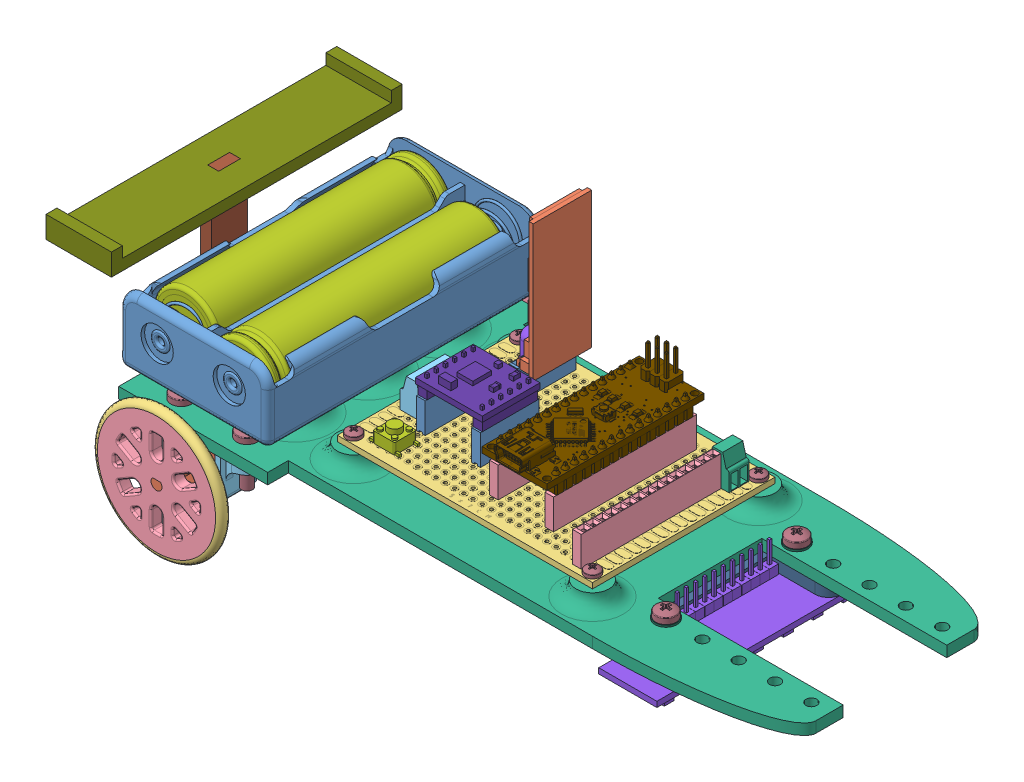
SolidWorks assembly LFR1_Assembly LFR, configuration Default. Lengths in mm.
Overall size (193.57 76.3 96.2).
59 component instances, 26 part files, 125 mates.
Components (placement in the parent):
- Battery holder 2 x 18650-1: Battery holder 2 x 18650 [Default] at (0 30.75 0) x (0 0 -1) z (0 1 0) size (76 41.1 19)
- Micro Metal Gear Motor-1: Micro Metal Gear Motor [Default] at (0 17.75 29) size (12 10 35.9)
- Micro Metal Gear Motor-2: Micro Metal Gear Motor [Default] at (0 17.75 -29) x (-1 0 0) z (0 0 -1) size (12 10 35.9)
- O-ring 29.5 x 3-1: O-ring 29.5 x 3 [Default] at (0 17.75 46.6) size (35.5 35.5 3)
- O-ring 29.5 x 3-2: O-ring 29.5 x 3 [Default] at (0 17.75 -46.6) size (35.5 35.5 3)
- Wiel 29.5 x 3-1: Wiel 29.5 x 3 [Default] at (0 17.75 46.6) size (32.5 32.5 3)
- Wiel 29.5 x 3-2: Wiel 29.5 x 3 [Default] at (0 17.75 -46.6) x (-1 0 0) z (0 0 -1) size (32.5 32.5 3)
- Micro Metal Gear Motor Bracket-1: Micro Metal Gear Motor Bracket [Default] at (0 22.75 33) x (-1 0 0) z (0 0 1) size (26.6 11.5 10)
- Micro Metal Gear Motor Bracket-2: Micro Metal Gear Motor Bracket [Default] at (0 22.75 -33) x (1 0 0) z (0 0 -1) size (26.6 11.5 10)
- Base-1: Base [Default] at (0 22.75 0) size (175.57 8.18 76)
- Battery 2 x 18650-1: Battery 2 x 18650 [Default] at (0 30.75 0) x (0 0 1) z (0 1 0) size (69.6 38.05 18.2)
- QTR-8A-2: QTR-8A [Default] at (114.575 18.25 0) x (0 0 -1) z (-1 0 0) size (66 11.64 16)
- M3 Ronde Kop-1: M3 Ronde Kop [Default] at (102.525 8 0) x (0 0 -1) z (1 0 0) size (5.77 15 5)
- QTR-8A plaatje-1: QTR-8A plaatje [Default] at (110.075 19.75 0) x (-1 0 0) z (0 0 -1) size (23.8 14.75 43.5)
- Spoiler deel 1-1: Spoiler deel 1 [Default] at (28 19.75 0) size (45.92 36 10)
- hex thin nut chamfered gradeab_iso-1: hex thin nut chamfered gradeab_iso [ISO - 4035 - M3 - C] at (-9.05 19.45 32.25) x (1 0 0) z (0 -1 0) size (5.5 6.35 1.8)
- hex thin nut chamfered gradeab_iso-2: hex thin nut chamfered gradeab_iso [ISO - 4035 - M3 - C] at (-9.05 19.45 -32.25) x (1 0 0) z (0 -1 0) size (5.5 6.35 1.8)
- hex thin nut chamfered gradeab_iso-3: hex thin nut chamfered gradeab_iso [ISO - 4035 - M3 - C] at (9.05 21.25 -32.25) x (-0.5 0 0.866025) z (0 1 0) size (5.5 6.35 1.8)
- hex thin nut chamfered gradeab_iso-4: hex thin nut chamfered gradeab_iso [ISO - 4035 - M3 - C] at (9.05 19.45 32.25) x (1 0 0) z (0 -1 0) size (5.5 6.35 1.8)
- pan head cross recess screw_iso-13: pan head cross recess screw_iso [ISO 7045 - M3 x 12 - Z - 12N] at (-9.05 28.15 -32.25) x (0 -1 0) z (0 0 1) size (14.35 5.6 5.6)
- pan head cross recess screw_iso-14: pan head cross recess screw_iso [ISO 7045 - M3 x 12 - Z - 12N] at (9.05 28.15 32.25) x (0 -1 0) z (0 0 1) size (14.35 5.6 5.6)
- pan head cross recess screw_iso-15: pan head cross recess screw_iso [ISO 7045 - M3 x 12 - Z - 12N] at (9.05 28.15 -32.25) x (0 -1 0) z (0 0 1) size (14.35 5.6 5.6)
- pan head cross recess screw_iso-16: pan head cross recess screw_iso [ISO 7045 - M3 x 12 - Z - 12N] at (-9.05 28.15 32.25) x (0 -1 0) z (0 0 1) size (14.35 5.6 5.6)
- hex thin nut chamfered gradeab_iso-5: hex thin nut chamfered gradeab_iso [ISO - 4035 - M3 - C] at (-9.925 19.75 0) x (1 0 0) z (0 1 0) size (5.5 6.35 1.8)
- hex thin nut chamfered gradeab_iso-6: hex thin nut chamfered gradeab_iso [ISO - 4035 - M3 - C] at (9.925 19.75 0) x (1 0 0) z (0 1 0) size (5.5 6.35 1.8)
- countersunk flat head cross recess screw_iso-4: countersunk flat head cross recess screw_iso [ISO 7046-1 - M3 x 16 - Z - 16N] at (9.925 32.65 0) x (0 -1 0) z (0 0 1) size (16 5.5 5.5)
- countersunk flat head cross recess screw_iso-5: countersunk flat head cross recess screw_iso [ISO 7046-1 - M3 x 16 - Z - 16N] at (-9.925 32.65 0) x (0 -1 0) z (0 0 1) size (16 5.5 5.5)
- pan head cross recess screw_iso-19: pan head cross recess screw_iso [ISO 7045 - M2 x 6 - Z - 6N] at (29 32.89 22.85) x (0 -1 0) z (0 0 1) size (7.57 4 4)
- pan head cross recess screw_iso-20: pan head cross recess screw_iso [ISO 7045 - M2 x 6 - Z - 6N] at (94.7 32.89 -22.85) x (0 -1 0) z (1 0 0) size (7.57 4 4)
- pan head cross recess screw_iso-21: pan head cross recess screw_iso [ISO 7045 - M2 x 6 - Z - 6N] at (29 32.89 -22.85) x (0 -1 0) z (0 0 1) size (7.57 4 4)
- pan head cross recess screw_iso-22: pan head cross recess screw_iso [ISO 7045 - M2 x 6 - Z - 6N] at (94.7 32.89 22.85) x (0 -1 0) z (0 0 1) size (7.57 4 4)
- plain washer small grade a_iso-1: plain washer small grade a_iso [Washer ISO 7092 - 2] at (94.7 29.75 22.85) x (0 -1 0) z (0 0 1) size (0.3 4.5 4.5)
- plain washer small grade a_iso-2: plain washer small grade a_iso [Washer ISO 7092 - 2] at (29 29.75 22.85) x (0 -1 0) z (0 0 1) size (0.3 4.5 4.5)
- plain washer small grade a_iso-3: plain washer small grade a_iso [Washer ISO 7092 - 2] at (94.7 29.75 -22.85) x (0 -1 0) z (0 0 1) size (0.3 4.5 4.5)
- plain washer small grade a_iso-4: plain washer small grade a_iso [Washer ISO 7092 - 2] at (29 29.75 -22.85) x (0 -1 0) z (0 0 1) size (0.3 4.5 4.5)
- plain washer small grade a_iso-5: plain washer small grade a_iso [Washer ISO 7092 - 3] at (110.075 18.25 -18) x (0 1 0) z (-1 0 0) size (0.5 6 6)
- plain washer small grade a_iso-6: plain washer small grade a_iso [Washer ISO 7092 - 3] at (110.075 18.25 18) x (0 1 0) z (-1 0 0) size (0.5 6 6)
- plain washer small grade a_iso-7: plain washer small grade a_iso [Washer ISO 7092 - 3] at (110.075 25.75 18) x (0 -1 0) z (-1 0 0) size (0.5 6 6)
- plain washer small grade a_iso-8: plain washer small grade a_iso [Washer ISO 7092 - 3] at (110.075 25.75 -18) x (0 -1 0) z (-1 0 0) size (0.5 6 6)
- pan head cross recess screw_iso-23: pan head cross recess screw_iso [ISO 7045 - M3 x 10 - Z - 10N] at (110.075 28.65 18) x (0 -1 0) z (-1 0 0) size (12.35 5.6 5.6)
- pan head cross recess screw_iso-24: pan head cross recess screw_iso [ISO 7045 - M3 x 10 - Z - 10N] at (110.075 28.65 -18) x (0 -1 0) z (-1 0 0) size (12.35 5.6 5.6)
- hex thin nut chamfered gradeab_iso-7: hex thin nut chamfered gradeab_iso [ISO - 4035 - M3 - C] at (110.075 15.95 18) x (-1 0 0) z (0 -1 0) size (5.5 6.35 1.8)
- hex thin nut chamfered gradeab_iso-8: hex thin nut chamfered gradeab_iso [ISO - 4035 - M3 - C] at (110.075 15.95 -18) x (-1 0 0) z (0 -1 0) size (5.5 6.35 1.8)
- Spoiler deel 2-1: Spoiler deel 2 [Default] at (-29.5 52.75 0) size (18 6 80)
- PCB assembly-1: PCB assembly [Default] at (61.85 29.75 0) size (70.2 48.6 50.2)
  - DRV8833-1: DRV8833 [Default] at (-16.49 13.955 5.08) size (18.4 11.9 15.9)
  - Arduino Nano-1: Arduino Nano [Default] at (16.8088 23.6188 0.3902) x (0 0 1) z (-1 0 0) size (44.95 20.74 17.81)
  - Header6P-1: Header6P [Default] at (-24.09 1.555 -1.27) x (0 0 1) z (0 1 0) size (16.1 2.4 11.5)
  - Header6P-2: Header6P [Default] at (-8.89 1.555 -1.27) x (0 0 1) z (0 1 0) size (16.1 2.4 11.5)
  - HC-05-2: HC-05 [Varsayılan] at (-13.49 46.555 -23.29) x (0 -1 0) z (-1 0 0) size (42.6 16.1 5.9)
  - Header6P-3: Header6P [Default] at (-19.04 1.555 -21.59) x (0 0 1) z (0 1 0) size (16.1 2.4 11.5)
  - PCB 50 x 70-1: PCB 50 x 70 [Default] x (1 0 0) z (0 1 0) size (70.2 50.2 1.66)
  - Header15P-1: Header15P [Default] at (1.2888 2.355 16.51) x (0 0 1) z (0 1 0) size (39.38 2.4 11.5)
  - Header15P-2: Header15P [Default] at (16.51 2.355 16.51) x (0 0 1) z (0 1 0) size (39.38 2.4 11.5)
  - Header15P-3: Header15P [Default] at (29.21 2.355 -13.97) x (0 0 -1) z (0 1 0) size (39.38 2.4 11.5)
  - ScrewTerminal x 4-1: ScrewTerminal x 4 [Default] at (-29.4 1.555 5.08) x (0 0 1) z (-1 0 0) size (10.62 12.4 6.3)
  - ScrewTerminal x 2-1: ScrewTerminal x 2 [Default] at (29.41 1.555 -17.78) x (0 0 -1) z (1 0 0) size (5.54 12.4 6.3)
  - Push button-1: Push button [Default] at (-25.39 1.555 19.05) size (8.26 7.7 6)
  - Led-1: Led [Default] at (-25.39 1.555 -19.05) size (5.8 11.9 5.8)
Mates (geometry in assembly coordinates):
- Concentric1: concentric anti-aligned: cylinder of Micro Metal Gear Motor-1 through (0 17.75 48.1) axis (0 0 -1) radius 1.5; cylinder of Micro Metal Gear Motor-2 through (0 17.75 -48.1) axis (0 0 1) radius 1.5
- Coincident32: coincident aligned: plane of Micro Metal Gear Motor-1 through (3.1623 22.75 15) normal (0 1 0); plane of Micro Metal Gear Motor-2 through (-3.1623 22.75 -15) normal (0 1 0)
- Concentric2: concentric anti-aligned: cylinder of Micro Metal Gear Motor-1 through (0 17.75 48.1) axis (0 0 -1) radius 1.5; line of O-ring 29.5 x 3-1 through (0 17.75 44.95) axis (0 0 1)
- Concentric3: concentric aligned: cylinder of Micro Metal Gear Motor-2 through (0 17.75 -48.1) axis (0 0 1) radius 1.5; line of O-ring 29.5 x 3-2 through (0 17.75 -48.25) axis (0 0 1)
- Coincident36: coincident aligned: plane of Micro Metal Gear Motor-1 through (0 17.75 48.1) normal (0 0 1); plane of Wiel 29.5 x 3-1 through (0 17.75 48.1) normal (0 0 1)
- Coincident37: coincident aligned: plane of O-ring 29.5 x 3-1 through (0 17.75 46.6) normal (0 0 1); plane of Wiel 29.5 x 3-1 through (0 17.75 46.6) normal (0 0 1)
- Coincident38: coincident anti-aligned: plane of O-ring 29.5 x 3-2 through (0 17.75 -46.6) normal (0 0 1); plane of Wiel 29.5 x 3-2 through (0 17.75 -46.6) normal (0 0 -1)
- Coincident40: coincident aligned: plane of Micro Metal Gear Motor-2 through (0 17.75 -48.1) normal (0 0 -1); plane of Wiel 29.5 x 3-2 through (0 17.75 -48.1) normal (0 0 -1)
- Coincident42: coincident aligned: plane of O-ring 29.5 x 3-1 through (0 17.75 46.6) normal (0 1 0); plane of O-ring 29.5 x 3-2 through (0 17.75 -46.6) normal (0 1 0)
- Coincident43: coincident aligned: plane of O-ring 29.5 x 3-1 through (0 17.75 46.6) normal (0 1 0); plane of Wiel 29.5 x 3-1 through (0 17.75 46.6) normal (0 1 0)
- Coincident46: coincident anti-aligned: plane of Micro Metal Gear Motor-1 through (6 22.25 37.2) normal (1 0 0); plane of Micro Metal Gear Motor Bracket-1 through (6 22.75 38) normal (-1 0 0)
- Coincident47: coincident anti-aligned: plane of Micro Metal Gear Motor-1 through (5.5 12.75 37.2) normal (0 -1 0); plane of Micro Metal Gear Motor Bracket-1 through (6 12.75 38) normal (0 1 0)
- Coincident48: coincident aligned: plane of Micro Metal Gear Motor-1 through (-5.5 13.25 38) normal (0 0 1); plane of Micro Metal Gear Motor Bracket-1 through (0 22.75 38) normal (0 0 1)
- Coincident50: coincident anti-aligned: plane of Micro Metal Gear Motor-2 through (-3.1623 12.75 -15) normal (0 -1 0); plane of Micro Metal Gear Motor Bracket-2 through (-6 12.75 -38) normal (0 1 0)
- Concentric6: concentric anti-aligned: cylinder of Micro Metal Gear Motor Bracket-1 through (-9.05 19.75 32.25) axis (0 1 0) radius 1.5; cylinder of Base-1 through (-9.05 25.75 32.25) axis (0 -1 0) radius 1.5
- Concentric11: concentric anti-aligned: cylinder of Battery holder 2 x 18650-1 through (-9.925 -55.8026 0) axis (0 1 0) radius 1.55; cylinder of Base-1 through (-9.925 25.75 0) axis (0 -1 0) radius 1.25
- Concentric12: concentric anti-aligned: cylinder of Battery holder 2 x 18650-1 through (9.925 -55.8026 0) axis (0 1 0) radius 1.55; cylinder of Base-1 through (9.925 25.75 0) axis (0 -1 0) radius 1.25
- Coincident55: coincident anti-aligned: plane of Micro Metal Gear Motor Bracket-2 through (6 22.75 -38) normal (0 1 0); plane of Base-1 through (0 22.75 0) normal (0 -1 0)
- Coincident56: coincident aligned: plane of Base-1 through (0 22.75 0) normal (0 0 1)
- Concentric16: concentric anti-aligned: cylinder of Micro Metal Gear Motor Bracket-2 through (-9.05 19.75 -32.25) axis (0 1 0) radius 1.5; cylinder of Base-1 through (-9.05 25.75 -32.25) axis (0 -1 0) radius 1.5
- Concentric17: concentric anti-aligned: cylinder of Micro Metal Gear Motor Bracket-2 through (9.05 19.75 -32.25) axis (0 1 0) radius 1.5; cylinder of Base-1 through (9.05 25.75 -32.25) axis (0 -1 0) radius 1.5
- Coincident61: coincident aligned: plane of Micro Metal Gear Motor-2 through (5.5 13.25 -38) normal (0 0 -1); plane of Micro Metal Gear Motor Bracket-2 through (0 22.75 -38) normal (0 0 -1)
- Coincident62: coincident aligned: plane of O-ring 29.5 x 3-1 through (0 0 46.6) normal (0 1 0)
- Coincident64: coincident aligned: plane of Base-1 through (0 22.75 0) normal (1 0 0)
- Concentric22: concentric anti-aligned: cylinder of Micro Metal Gear Motor Bracket-1 through (-9.05 19.75 32.25) axis (0 1 0) radius 1.5; cylinder of hex thin nut chamfered gradeab_iso-1 through (-9.05 21.25 32.25) axis (0 -1 0) radius 1.25
- Coincident76: coincident anti-aligned: plane of Micro Metal Gear Motor Bracket-1 through (-11.8 21.25 33.8377) normal (1 0 0); plane of hex thin nut chamfered gradeab_iso-1 through (-11.8 21.25 33.8377) normal (-1 0 0)
- Coincident77: coincident anti-aligned: plane of Micro Metal Gear Motor Bracket-1 through (0 21.25 33) normal (0 -1 0); plane of hex thin nut chamfered gradeab_iso-1 through (-9.05 21.25 35.4254) normal (0 1 0)
- Concentric23: concentric anti-aligned: cylinder of Micro Metal Gear Motor Bracket-1 through (9.05 19.75 32.25) axis (0 1 0) radius 1.5; cylinder of hex thin nut chamfered gradeab_iso-4 through (9.05 21.25 32.25) axis (0 -1 0) radius 1.25
- Coincident78: coincident anti-aligned: plane of Micro Metal Gear Motor Bracket-1 through (11.8 21.25 30.6623) normal (-1 0 0); plane of hex thin nut chamfered gradeab_iso-4 through (11.8 21.25 33.8377) normal (1 0 0)
- Coincident79: coincident anti-aligned: plane of Micro Metal Gear Motor Bracket-1 through (0 21.25 33) normal (0 -1 0); plane of hex thin nut chamfered gradeab_iso-4 through (9.05 21.25 35.4254) normal (0 1 0)
- Concentric24: concentric anti-aligned: cylinder of Base-1 through (9.05 25.75 -32.25) axis (0 -1 0) radius 1.5; cylinder of hex thin nut chamfered gradeab_iso-3 through (9.05 19.45 -32.25) axis (0 1 0) radius 1.25
- Coincident80: coincident anti-aligned: plane of Micro Metal Gear Motor Bracket-2 through (11.8 21.25 -33.8377) normal (-1 0 0); plane of hex thin nut chamfered gradeab_iso-3 through (11.8 19.45 -30.6623) normal (1 0 0)
- Coincident81: coincident anti-aligned: plane of Micro Metal Gear Motor Bracket-2 through (0 21.25 -33) normal (0 -1 0); plane of hex thin nut chamfered gradeab_iso-3 through (11.8 21.25 -30.6623) normal (0 1 0)
- Concentric25: concentric anti-aligned: cylinder of Micro Metal Gear Motor Bracket-2 through (-9.05 19.75 -32.25) axis (0 1 0) radius 1.5; cylinder of hex thin nut chamfered gradeab_iso-2 through (-9.05 21.25 -32.25) axis (0 -1 0) radius 1.25
- Coincident82: coincident anti-aligned: plane of Micro Metal Gear Motor Bracket-2 through (-11.8 21.25 -30.6623) normal (1 0 0); plane of hex thin nut chamfered gradeab_iso-2 through (-11.8 21.25 -30.6623) normal (-1 0 0)
- Coincident83: coincident anti-aligned: plane of Micro Metal Gear Motor Bracket-2 through (0 21.25 -33) normal (0 -1 0); plane of hex thin nut chamfered gradeab_iso-2 through (-9.05 21.25 -29.0746) normal (0 1 0)
- Coincident85: coincident aligned: plane of pan head cross recess screw_iso-14 through (10.55 25.75 32.25) normal (0 -1 0); plane of pan head cross recess screw_iso-15 through (10.55 25.75 -32.25) normal (0 -1 0)
- Coincident86: coincident aligned: plane of pan head cross recess screw_iso-15 through (10.55 25.75 -32.25) normal (0 -1 0); plane of pan head cross recess screw_iso-16 through (-7.55 25.75 32.25) normal (0 -1 0)
- Coincident87: coincident aligned: plane of pan head cross recess screw_iso-13 through (-7.55 25.75 -32.25) normal (0 -1 0); plane of pan head cross recess screw_iso-14 through (10.55 25.75 32.25) normal (0 -1 0)
- Coincident90: coincident anti-aligned: plane of Base-1 through (0 25.75 0) normal (0 1 0); plane of pan head cross recess screw_iso-15 through (10.55 25.75 -32.25) normal (0 -1 0)
- Concentric28: concentric aligned: cylinder of hex thin nut chamfered gradeab_iso-3 through (9.05 19.45 -32.25) axis (0 1 0) radius 1.25; cylinder of pan head cross recess screw_iso-15 through (9.05 53.55 -32.25) axis (0 1 0) radius 1.5
- Concentric29: concentric anti-aligned: cylinder of hex thin nut chamfered gradeab_iso-4 through (9.05 21.25 32.25) axis (0 -1 0) radius 1.25; cylinder of pan head cross recess screw_iso-14 through (9.05 53.55 32.25) axis (0 1 0) radius 1.5
- Concentric30: concentric anti-aligned: cylinder of hex thin nut chamfered gradeab_iso-2 through (-9.05 21.25 -32.25) axis (0 -1 0) radius 1.25; cylinder of pan head cross recess screw_iso-13 through (-9.05 53.55 -32.25) axis (0 1 0) radius 1.5
- Concentric31: concentric anti-aligned: cylinder of hex thin nut chamfered gradeab_iso-1 through (-9.05 21.25 32.25) axis (0 -1 0) radius 1.25; cylinder of pan head cross recess screw_iso-16 through (-9.05 53.55 32.25) axis (0 1 0) radius 1.5
- Parallel16: parallel aligned: plane of pan head cross recess screw_iso-13 through (-9.05 28.15 -32.25) normal (0 0 1); plane of pan head cross recess screw_iso-14 through (9.05 28.15 32.25) normal (0 0 1)
- Parallel17: parallel aligned: plane of pan head cross recess screw_iso-14 through (9.05 28.15 32.25) normal (0 0 1); plane of pan head cross recess screw_iso-15 through (9.05 28.15 -32.25) normal (0 0 1)
- Parallel18: parallel aligned: plane of pan head cross recess screw_iso-15 through (9.05 28.15 -32.25) normal (0 0 1); plane of pan head cross recess screw_iso-16 through (-9.05 28.15 32.25) normal (0 0 1)
- Parallel19: parallel aligned: plane of pan head cross recess screw_iso-16 through (-9.05 28.15 32.25) normal (0 0 1)
- Coincident97: coincident aligned: plane of hex thin nut chamfered gradeab_iso-5 through (-9.925 19.75 -3.1754) normal (0 1 0); plane of hex thin nut chamfered gradeab_iso-6 through (9.925 19.75 -3.1754) normal (0 1 0)
- Coincident98: coincident anti-aligned: plane of Spoiler deel 1-1 through (28 19.75 -5) normal (0 -1 0); plane of hex thin nut chamfered gradeab_iso-5 through (-9.925 19.75 -3.1754) normal (0 1 0)
- Parallel20: parallel aligned: plane of hex thin nut chamfered gradeab_iso-5 through (-12.675 17.95 -1.5877) normal (-1 0 0); plane of hex thin nut chamfered gradeab_iso-6 through (7.175 17.95 -1.5877) normal (-1 0 0)
- Parallel21: parallel aligned: plane of hex thin nut chamfered gradeab_iso-2 through (-11.8 21.25 -30.6623) normal (-1 0 0); plane of hex thin nut chamfered gradeab_iso-5 through (-12.675 17.95 -1.5877) normal (-1 0 0)
- Coincident103: coincident aligned: plane of countersunk flat head cross recess screw_iso-4 through (9.925 32.65 0) normal (0 0 1); plane of countersunk flat head cross recess screw_iso-5 through (-9.925 32.65 0) normal (0 0 1)
- Coincident104: coincident aligned: plane of Battery holder 2 x 18650-1 through (0 32.65 0) normal (0 1 0); plane of countersunk flat head cross recess screw_iso-4 through (9.925 32.65 0) normal (0 1 0)
- Concentric36: concentric anti-aligned: cylinder of Base-1 through (-9.925 25.75 0) axis (0 -1 0) radius 1.25; cylinder of countersunk flat head cross recess screw_iso-5 through (-9.925 39 0) axis (0 1 0) radius 1.5
- Concentric37: concentric aligned: cylinder of hex thin nut chamfered gradeab_iso-5 through (-9.925 17.95 0) axis (0 1 0) radius 1.25; cylinder of countersunk flat head cross recess screw_iso-5 through (-9.925 39 0) axis (0 1 0) radius 1.5
- Concentric38: concentric aligned: cylinder of hex thin nut chamfered gradeab_iso-6 through (9.925 17.95 0) axis (0 1 0) radius 1.25; cylinder of countersunk flat head cross recess screw_iso-4 through (9.925 39 0) axis (0 1 0) radius 1.5
- Concentric39: concentric anti-aligned: cylinder of Base-1 through (9.925 25.75 0) axis (0 -1 0) radius 1.25; cylinder of countersunk flat head cross recess screw_iso-4 through (9.925 39 0) axis (0 1 0) radius 1.5
- Coincident105: coincident aligned: plane of countersunk flat head cross recess screw_iso-4 through (9.925 32.65 0) normal (0 1 0); plane of countersunk flat head cross recess screw_iso-5 through (-9.925 32.65 0) normal (0 1 0)
- Coincident106: coincident anti-aligned: plane of Battery holder 2 x 18650-1 through (0 30.75 0) normal (0 -1 0); plane of Base-1 through (-9.925 30.75 -20) normal (0 1 0)
- Coincident1071: coincident aligned: plane of pan head cross recess screw_iso-21 through (30 31.29 -22.85) normal (0 -1 0); plane of pan head cross recess screw_iso-22 through (95.7 31.29 22.85) normal (0 -1 0)
- Coincident1081: coincident aligned: plane of pan head cross recess screw_iso-19 through (30 31.29 22.85) normal (0 -1 0); plane of pan head cross recess screw_iso-21 through (30 31.29 -22.85) normal (0 -1 0)
- Coincident1091: coincident aligned: plane of pan head cross recess screw_iso-20 through (94.7 31.29 -23.85) normal (0 -1 0); plane of pan head cross recess screw_iso-22 through (95.7 31.29 22.85) normal (0 -1 0)
- Coincident1111: coincident aligned: plane of pan head cross recess screw_iso-20 through (94.358 31.47 -22.61) normal (0 0 -1); plane of pan head cross recess screw_iso-21 through (28.658 31.47 -22.61) normal (0 0 -1)
- Coincident1121: coincident aligned: plane of pan head cross recess screw_iso-19 through (28.658 31.47 23.09) normal (0 0 -1); plane of pan head cross recess screw_iso-22 through (94.358 31.47 23.09) normal (0 0 -1)
- Coincident1131: coincident aligned: plane of plain washer small grade a_iso-3 through (95.8 29.75 -22.85) normal (0 -1 0); plane of plain washer small grade a_iso-4 through (30.1 29.75 -22.85) normal (0 -1 0)
- Coincident1141: coincident aligned: plane of plain washer small grade a_iso-2 through (30.1 29.75 22.85) normal (0 -1 0); plane of plain washer small grade a_iso-4 through (30.1 29.75 -22.85) normal (0 -1 0)
- Coincident1151: coincident aligned: plane of plain washer small grade a_iso-1 through (95.8 29.75 22.85) normal (0 -1 0); plane of plain washer small grade a_iso-2 through (30.1 29.75 22.85) normal (0 -1 0)
- Coincident1171: coincident anti-aligned: plane of Base-1 through (24.5 29.75 22.85) normal (0 1 0); plane of plain washer small grade a_iso-2 through (30.1 29.75 22.85) normal (0 -1 0)
- Concentric441: concentric aligned: cylinder of pan head cross recess screw_iso-19 through (29 58.29 22.85) axis (0 1 0) radius 1; cylinder of plain washer small grade a_iso-2 through (29 64.675 22.85) axis (0 1 0) radius 1.1
- Concentric451: concentric aligned: cylinder of pan head cross recess screw_iso-22 through (94.7 58.29 22.85) axis (0 1 0) radius 1; cylinder of plain washer small grade a_iso-1 through (94.7 64.675 22.85) axis (0 1 0) radius 1.1
- Concentric461: concentric aligned: cylinder of pan head cross recess screw_iso-20 through (94.7 58.29 -22.85) axis (0 1 0) radius 1; cylinder of plain washer small grade a_iso-3 through (94.7 64.675 -22.85) axis (0 1 0) radius 1.1
- Concentric47: concentric aligned: cylinder of pan head cross recess screw_iso-21 through (29 58.29 -22.85) axis (0 1 0) radius 1; cylinder of plain washer small grade a_iso-4 through (29 64.675 -22.85) axis (0 1 0) radius 1.1
- Coincident1172: coincident anti-aligned: plane of Battery holder 2 x 18650-1 through (0 30.75 0) normal (-1 0 0); plane of Battery 2 x 18650-1 through (0 30.75 0) normal (1 0 0)
- Coincident1173: coincident anti-aligned: plane of Battery holder 2 x 18650-1 through (0 30.75 0) normal (0 0 -1); plane of Battery 2 x 18650-1 through (0 30.75 0) normal (0 0 1)
- Coincident1174: coincident aligned: plane of Battery holder 2 x 18650-1 through (0 30.75 0) normal (0 1 0); plane of Battery 2 x 18650-1 through (0 30.75 0) normal (0 1 0)
- Coincident1175: coincident aligned: plane of plain washer small grade a_iso-1 through (94.7 29.75 22.85) normal (0 0 1); plane of plain washer small grade a_iso-2 through (29 29.75 22.85) normal (0 0 1)
- Coincident1176: coincident aligned: plane of plain washer small grade a_iso-3 through (94.7 29.75 -22.85) normal (0 0 1); plane of plain washer small grade a_iso-4 through (29 29.75 -22.85) normal (0 0 1)
- Coincident1178: coincident anti-aligned: plane of QTR-8A-2 through (114.575 18.25 0) normal (0 0 -1)
- Concentric462: concentric aligned: cylinder of QTR-8A-2 through (110.075 19.75 18) axis (0 -1 0) radius 1.5; cylinder of QTR-8A plaatje-1 through (110.075 22.75 18) axis (0 -1 0) radius 1.5
- Coincident1179: coincident anti-aligned: plane of QTR-8A plaatje-1 through (118.825 19.75 18) normal (0 -1 0); plane of QTR-8A-2 through (114.575 19.75 0) normal (0 1 0)
- Coincident1180: coincident aligned: plane of plain washer small grade a_iso-5 through (110.075 18.25 -19.6) normal (0 1 0); plane of plain washer small grade a_iso-6 through (110.075 18.25 16.4) normal (0 1 0)
- Coincident1181: coincident anti-aligned: plane of QTR-8A-2 through (114.575 18.25 0) normal (0 -1 0); plane of plain washer small grade a_iso-6 through (110.075 18.25 16.4) normal (0 1 0)
- Concentric463: concentric aligned: cylinder of QTR-8A-2 through (110.075 19.75 18) axis (0 -1 0) radius 1.5; cylinder of plain washer small grade a_iso-6 through (110.075 -16.675 18) axis (0 -1 0) radius 1.6
- Concentric464: concentric aligned: cylinder of QTR-8A-2 through (110.075 19.75 -18) axis (0 -1 0) radius 1.5; cylinder of plain washer small grade a_iso-5 through (110.075 -16.675 -18) axis (0 -1 0) radius 1.6
- Coincident1182: coincident aligned: plane of plain washer small grade a_iso-7 through (110.075 25.75 19.6) normal (0 -1 0); plane of plain washer small grade a_iso-8 through (110.075 25.75 -16.4) normal (0 -1 0)
- Coincident1183: coincident anti-aligned: plane of Base-1 through (0 25.75 0) normal (0 1 0); plane of plain washer small grade a_iso-7 through (110.075 25.75 19.6) normal (0 -1 0)
- Concentric465: concentric anti-aligned: cylinder of plain washer small grade a_iso-8 through (110.075 60.675 -18) axis (0 1 0) radius 1.6; cylinder of QTR-8A plaatje-1 through (110.075 22.75 -18) axis (0 -1 0) radius 1.5
- Concentric466: concentric anti-aligned: cylinder of plain washer small grade a_iso-7 through (110.075 60.675 18) axis (0 1 0) radius 1.6; cylinder of QTR-8A plaatje-1 through (110.075 22.75 18) axis (0 -1 0) radius 1.5
- Coincident1184: coincident aligned: plane of plain washer small grade a_iso-5 through (110.075 18.25 -18) normal (-1 0 0); plane of plain washer small grade a_iso-6 through (110.075 18.25 18) normal (-1 0 0)
- Coincident1185: coincident aligned: plane of plain washer small grade a_iso-7 through (110.075 25.75 18) normal (-1 0 0); plane of plain washer small grade a_iso-8 through (110.075 25.75 -18) normal (-1 0 0)
- Coincident1186: coincident aligned: plane of pan head cross recess screw_iso-23 through (110.075 26.25 19.5) normal (0 -1 0); plane of pan head cross recess screw_iso-24 through (110.075 26.25 -16.5) normal (0 -1 0)
- Coincident1187: coincident aligned: plane of pan head cross recess screw_iso-23 through (110.445 26.9 18.5275) normal (-1 0 0); plane of pan head cross recess screw_iso-24 through (110.445 26.9 -17.4725) normal (-1 0 0)
- Concentric468: concentric anti-aligned: cylinder of pan head cross recess screw_iso-24 through (110.075 54.05 -18) axis (0 1 0) radius 1.5; cylinder of QTR-8A plaatje-1 through (110.075 22.75 -18) axis (0 -1 0) radius 1.5
- Concentric469: concentric anti-aligned: cylinder of pan head cross recess screw_iso-23 through (110.075 54.05 18) axis (0 1 0) radius 1.5; cylinder of QTR-8A plaatje-1 through (110.075 22.75 18) axis (0 -1 0) radius 1.5
- Coincident1188: coincident anti-aligned: plane of plain washer small grade a_iso-7 through (110.075 26.25 21) normal (0 1 0); plane of pan head cross recess screw_iso-23 through (110.075 26.25 19.5) normal (0 -1 0)
- Coincident1189: coincident aligned: plane of hex thin nut chamfered gradeab_iso-7 through (110.075 15.95 14.8246) normal (0 -1 0); plane of hex thin nut chamfered gradeab_iso-8 through (110.075 15.95 -21.1754) normal (0 -1 0)
- Coincident1190: coincident aligned: plane of hex thin nut chamfered gradeab_iso-7 through (107.325 17.75 16.4123) normal (-1 0 0); plane of hex thin nut chamfered gradeab_iso-8 through (107.325 17.75 -19.5877) normal (-1 0 0)
- Concentric470: concentric aligned: cylinder of hex thin nut chamfered gradeab_iso-7 through (110.075 17.75 18) axis (0 -1 0) radius 1.25; cylinder of QTR-8A plaatje-1 through (110.075 22.75 18) axis (0 -1 0) radius 1.5
- Coincident1191: coincident anti-aligned: plane of plain washer small grade a_iso-6 through (110.075 17.75 15) normal (0 -1 0); plane of hex thin nut chamfered gradeab_iso-7 through (110.075 17.75 14.8246) normal (0 1 0)
- Coincident1194: coincident anti-aligned: plane of M3 Ronde Kop-1 through (102.525 8 0) normal (0 0 -1)
- Coincident1195: coincident anti-aligned: plane of Base-1 through (0 22.75 0) normal (0 -1 0); plane of QTR-8A plaatje-1 through (118.825 22.75 18) normal (0 1 0)
- Concentric475: concentric anti-aligned: cylinder of QTR-8A plaatje-1 through (110.075 22.75 18) axis (0 -1 0) radius 1.5; cylinder of Base-1 through (110.075 -31.2488 18) axis (0 1 0) radius 1.5
- Coincident1198: coincident aligned: plane of M3 Ronde Kop-1 through (102.525 0 0) normal (0 1 0)
- Concentric476: concentric anti-aligned: cylinder of M3 Ronde Kop-1 through (102.525 0 0) axis (0 -1 0) radius 1.5; cylinder of QTR-8A plaatje-1 through (102.525 19.75 0) axis (0 1 0) radius 1.25
- Concentric477: concentric aligned: cylinder of QTR-8A-2 through (110.075 19.75 -18) axis (0 -1 0) radius 1.5; cylinder of hex thin nut chamfered gradeab_iso-8 through (110.075 17.75 -18) axis (0 -1 0) radius 1.25
- Concentric478: concentric anti-aligned: cylinder of Micro Metal Gear Motor-1 through (0 17.75 48.1) axis (0 0 -1) radius 1.5; cylinder of Wiel 29.5 x 3-1 through (0 17.75 41.1949) axis (0 0 1) radius 1.5
- Parallel24: parallel anti-aligned: plane of Wiel 29.5 x 3-2 through (16.25 17.75 -45.1) normal (0 0 1); plane of Base-1 through (-20.5 25.75 -38) normal (0 0 -1)
- Concentric479: concentric anti-aligned: cylinder of Micro Metal Gear Motor-2 through (0 17.75 -48.1) axis (0 0 1) radius 1.5; cylinder of Wiel 29.5 x 3-2 through (0 17.75 -41.1949) axis (0 0 -1) radius 1.5
- Coincident1200: coincident anti-aligned: plane of Micro Metal Gear Motor-2 through (6 18.75 -48.1) normal (0 1 0); plane of Wiel 29.5 x 3-2 through (1.118 18.75 -41.1949) normal (0 -1 0)
- Coincident1202: coincident aligned: plane of Spoiler deel 1-1 through (28 19.75 0) normal (0 0 1)
- Coincident1203: coincident aligned: plane of Spoiler deel 1-1 through (28 19.75 0) normal (0 0 1)
- Concentric482: concentric anti-aligned: cylinder of Base-1 through (-9.925 25.75 0) axis (0 -1 0) radius 1.25; cylinder of Spoiler deel 1-1 through (-9.925 19.75 0) axis (0 1 0) radius 1.5
- Coincident1205: coincident anti-aligned: plane of Base-1 through (0 22.75 0) normal (0 -1 0); plane of Spoiler deel 1-1 through (28 22.75 -5) normal (0 1 0)
- Coincident1206: coincident aligned: line of Spoiler deel 1-1 through (-28 52.75 -3) axis (-1 0 0); line of Spoiler deel 2-1 through (-28 52.75 -3) axis (-1 0 0)
- Coincident1207: coincident anti-aligned: plane of Spoiler deel 1-1 through (28 52.75 -5) normal (0 1 0); plane of Spoiler deel 2-1 through (-29.5 52.75 0) normal (0 -1 0)
- Coincident1208: coincident anti-aligned: line of Spoiler deel 1-1 through (-28 55.75 -3) axis (0 0 1); line of Spoiler deel 2-1 through (-28 55.75 3) axis (0 0 -1)
- Coincident1209: coincident anti-aligned: plane of pan head cross recess screw_iso-21 through (30 31.29 -22.85) normal (0 -1 0); plane of PCB assembly-1/PCB 50 x 70-1 through (61.85 31.29 0) normal (0 1 0)
- Concentric483: concentric anti-aligned: cylinder of pan head cross recess screw_iso-19 through (29 58.29 22.85) axis (0 1 0) radius 1; cylinder of PCB assembly-1/PCB 50 x 70-1 through (29 29.75 22.85) axis (0 -1 0) radius 1.35
- Concentric484: concentric anti-aligned: cylinder of pan head cross recess screw_iso-22 through (94.7 58.29 22.85) axis (0 1 0) radius 1; cylinder of PCB assembly-1/PCB 50 x 70-1 through (94.7 29.75 22.85) axis (0 -1 0) radius 1.35
- Concentric485: concentric anti-aligned: cylinder of pan head cross recess screw_iso-20 through (94.7 58.29 -22.85) axis (0 1 0) radius 1; cylinder of PCB assembly-1/PCB 50 x 70-1 through (94.7 29.75 -22.85) axis (0 -1 0) radius 1.35
- Concentric486: concentric anti-aligned: cylinder of pan head cross recess screw_iso-21 through (29 58.29 -22.85) axis (0 1 0) radius 1; cylinder of PCB assembly-1/PCB 50 x 70-1 through (29 29.75 -22.85) axis (0 -1 0) radius 1.35
- Coincident1210: coincident anti-aligned: plane of Base-1 through (90.2 29.75 22.85) normal (0 1 0); plane of PCB assembly-1/PCB 50 x 70-1 through (61.85 29.75 0) normal (0 -1 0)
- Concentric487: concentric anti-aligned: cylinder of Base-1 through (29 25.75 22.85) axis (0 -1 0) radius 0.8; cylinder of pan head cross recess screw_iso-19 through (29 58.29 22.85) axis (0 1 0) radius 1
- Concentric488: concentric anti-aligned: cylinder of Base-1 through (94.7 25.75 -22.85) axis (0 -1 0) radius 0.8; cylinder of pan head cross recess screw_iso-20 through (94.7 58.29 -22.85) axis (0 1 0) radius 1
